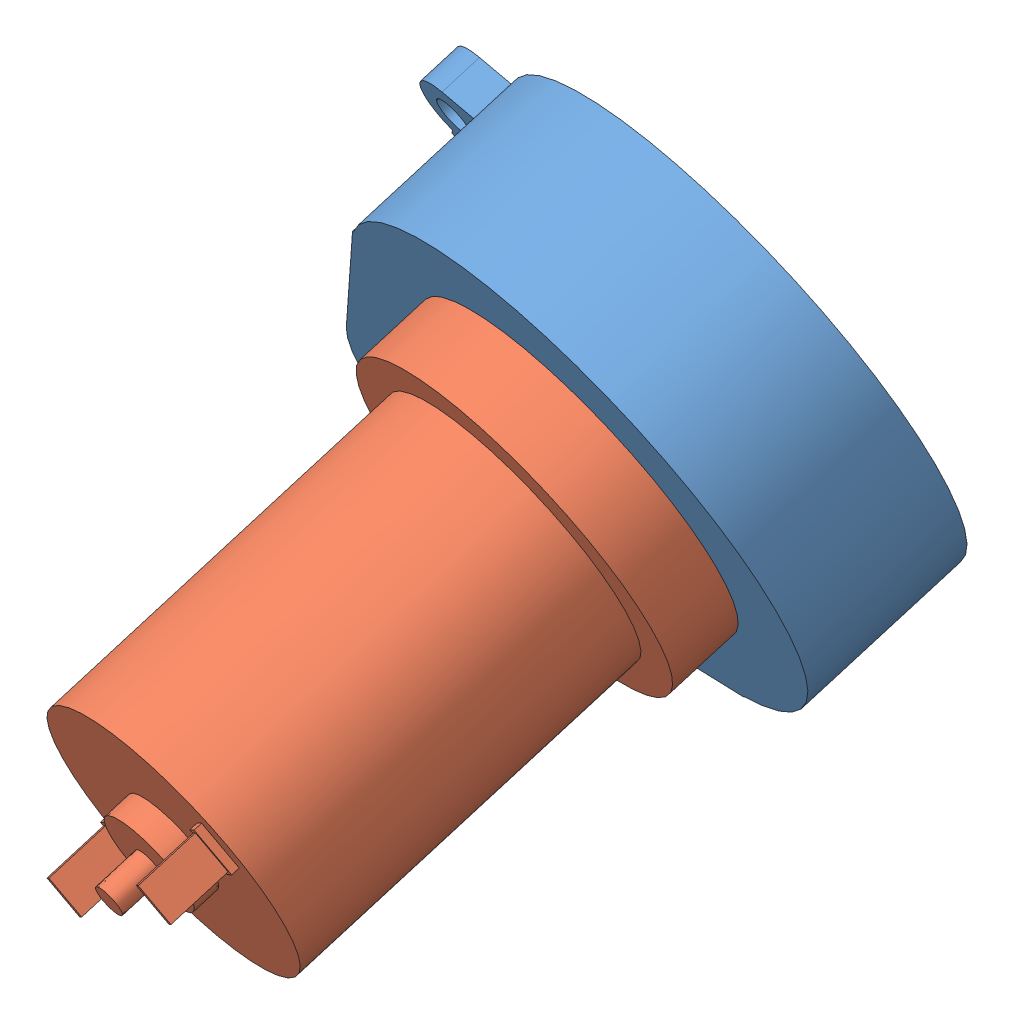
SolidWorks assembly Moto reducteur mdp RS 385, configuration Défaut. Lengths in mm.
Overall size (87.92 85.57 95.54).
2 component instances, 2 part files, 3 mates.
Components (placement in the parent):
- Reducteur mdp-1: Reducteur mdp [Défaut] at (-2.7572 10.5941 -25.3996) x (-0.625376 0.734673 0.262984) z (0.771281 0.530808 0.351239) size (55.4 20 66)
- Moteur mdp RS 385-1: Moteur mdp RS 385 [Défaut] at (15.668 17.4781 -0.8157) x (-0.625376 0.734673 0.262984) z (-0.118452 -0.422491 0.898594) size (35 35 50.3)
Mates (geometry in assembly coordinates):
- Coïncidente3: coincident aligned: axis of Reducteur mdp-1 through (15.668 17.4781 -0.8157) axis (0.118452 0.422491 -0.898594); axis of Moteur mdp RS 385-1 through (10.5272 -0.858 38.1833) axis (0.118452 0.422491 -0.898594)
- Parallèle2: parallel aligned: plane of Reducteur mdp-1 through (-3.4699 -18.6642 -20.3314) normal (-0.771281 -0.530808 -0.351239); plane of Moteur mdp RS 385-1 through (1.8595 -11.5061 39.713) normal (-0.771281 -0.530808 -0.351239)
- Coïncidente5: coincident anti-aligned: plane of Reducteur mdp-1 through (-9.7533 27.9444 0.7542) normal (-0.118452 -0.422491 0.898594); plane of Moteur mdp RS 385-1 through (15.668 17.4781 -0.8157) normal (0.118452 0.422491 -0.898594)
